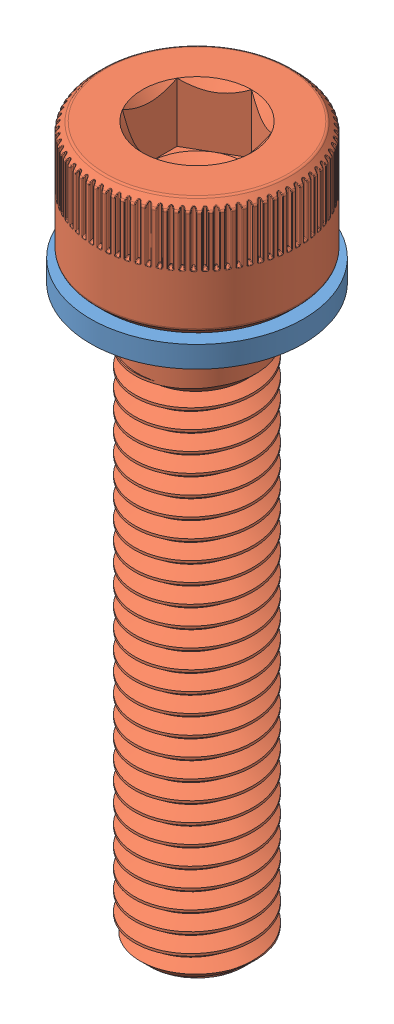
SolidWorks assembly linear_rail_carriage_mount_screw, configuration Default. Lengths in mm.
Overall size (11.63 30.66 11.63).
2 component instances, 2 part files, 5 mates.
Components (placement in the parent):
- m5 washer 98689A114_General Purpose 18-8 Stainless Steel Washer-1: m5 washer 98689A114_General Purpose 18-8 Stainless Steel Washer [98689A114] at (0 0.5 0) x (1 0 0) z (0 -1 0) size (9 9 1) (hidden)
- m5-25mm socket head 90128A249_Zinc-Plated Alloy Steel Socket Head Screw-1: m5-25mm socket head 90128A249_Zinc-Plated Alloy Steel Socket Head Screw [90128A249] at (0 -9 0) x (0.5 0 -0.866025) z (0 1 0) size (8.51 8.51 30.66)
Mates (geometry in assembly coordinates):
- Concentric3: concentric anti-aligned: cylinder of m5 washer 98689A114_General Purpose 18-8 Stainless Steel Washer-1 through (0 0 0) axis (0 -1 0) radius 2.65
- Tangent2: tangent anti-aligned: torus of m5 washer 98689A114_General Purpose 18-8 Stainless Steel Washer-1
- Concentric4: concentric anti-aligned: cylinder of m5 washer 98689A114_General Purpose 18-8 Stainless Steel Washer-1 through (0 0 0) axis (0 -1 0) radius 2.65; cylinder of m5-25mm socket head 90128A249_Zinc-Plated Alloy Steel Socket Head Screw-1 through (0 6 0) axis (0 1 0) radius 2.5
- Coincident1: coincident anti-aligned: plane of m5 washer 98689A114_General Purpose 18-8 Stainless Steel Washer-1 through (0 1 2.65) normal (0 1 0); plane of m5-25mm socket head 90128A249_Zinc-Plated Alloy Steel Socket Head Screw-1 through (-2.1651 1 -1.25) normal (0 -1 0)
- Parallel1: parallel anti-aligned: plane of m5-25mm socket head 90128A249_Zinc-Plated Alloy Steel Socket Head Screw-1 through (2 3.5 1.1547) normal (-1 0 0)
